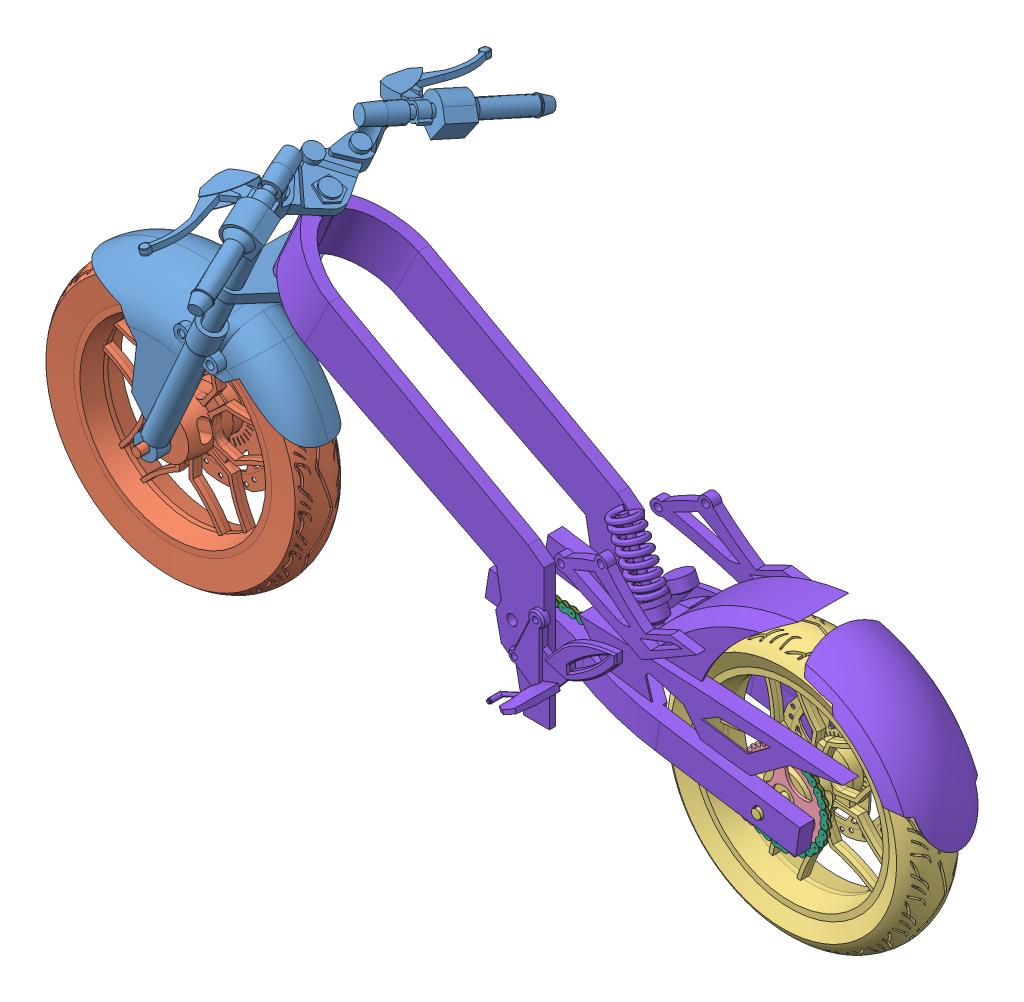
SolidWorks assembly Electric two wheeler, configuration Default. Lengths in mm.
Overall size (2197.87 1236.33 788.52).
90 component instances, 8 part files, 0 mates.
Components (placement in the parent):
- Electric two wheeler.asm-1: Electric two wheeler.asm [Default] at origin size (2197.87 1236.33 788.52)
  - RS 200 HANDLE BARS_0.par-1: RS 200 HANDLE BARS_0.par [Default] at (-2.4024 36.4669 0) x (0 0 -1) z (0.912692 -0.408647 0) size (788.52 788.56 502.86)
  - RS 200 wheel 1_0.par-1: RS 200 wheel 1_0.par [Default] at (-10.5753 18.2131 0) x (0.678244 0.734836 0) z (0 0 -1) size (605.54 605.71 250)
  - RS 200 wheel 2_0.par-1: RS 200 wheel 2_0.par [Default] at (1342.468 10.7356 0) x (-0.818471 0.574548 0) z (0 0 -1) size (598.74 598.38 250)
  - RS200 CHAIN ASSEMBLY_0.asm-1: RS200 CHAIN ASSEMBLY_0.asm [Default] at (1342.468 10.7356 63) x (0.986561 -0.163391 0) z (0 0 1) size (769.44 261.39 9)
    - RS200 45T_0.par-1: RS200 45T_0.par [Default] x (-0.88643 0.462862 0) z (0 0 1) size (193.8 193.68 6)
    - RS200 15T_0.par-1: RS200 15T_0.par [Default] at (-594 0 0) x (-0.272025 0.96229 0) z (0 0 1) size (72.25 71.85 6)
    - RS200 LINK MAIN_0.par-1: RS200 LINK MAIN_0.par [Default] at (-37.6918 -87.6334 0) x (-0.994799 0.101861 0) z (0 0 -1) size (37.05 18 9)
    - RS200 LINK MAIN_0.par-2: RS200 LINK MAIN_0.par [Default] at (0.2544 -91.0166 0) x (-0.994213 -0.10743 0) z (0 0 -1) size (37.05 18 9)
    - RS200 LINK MAIN_0.par-3: RS200 LINK MAIN_0.par [Default] at (37.293 -83.026 0) x (-0.864315 -0.50295 0) z (0 0 -1) size (37.05 18 9)
    - RS200 LINK MAIN_0.par-4: RS200 LINK MAIN_0.par [Default] at (67.8685 -60.6462 0) x (-0.584624 -0.811305 0) z (0 0 -1) size (37.05 18 9)
    - RS200 LINK MAIN_0.par-5: RS200 LINK MAIN_0.par [Default] at (86.6816 -27.7558 0) x (-0.203611 -0.979052 0) z (0 0 -1) size (37.05 18 9)
    - RS200 LINK MAIN_0.par-6: RS200 LINK MAIN_0.par [Default] at (90.472 9.945 0) x (0.212689 -0.97712 0) z (0 0 -1) size (37.05 18 9)
    - RS200 LINK MAIN_0.par-7: RS200 LINK MAIN_0.par [Default] at (78.5827 45.9221 0) x (0.592128 -0.805844 0) z (0 0 -1) size (37.05 18 9)
    - RS200 LINK MAIN_0.par-8: RS200 LINK MAIN_0.par [Default] at (53.0743 73.9406 0) x (0.868946 -0.494907 0) z (0 0 -1) size (37.05 18 9)
    - RS200 LINK MAIN_0.par-9: RS200 LINK MAIN_0.par [Default] at (18.3675 89.1444 0) x (0.995167 -0.098198 0) z (0 0 -1) size (37.05 18 9)
    - RS200 LINK MAIN_0.par-10: RS200 LINK MAIN_0.par [Default] at (-19.5791 89.4881 0) x (0.994799 0.101861 0) z (0 0 -1) size (37.05 18 9)
    - RS200 LINK MAIN_0.par-11: RS200 LINK MAIN_0.par [Default] at (-57.4809 85.6071 0) x (0.994799 0.101861 0) z (0 0 -1) size (37.05 18 9)
    - RS200 LINK MAIN_0.par-12: RS200 LINK MAIN_0.par [Default] at (-95.3827 81.7262 0) x (0.994799 0.101861 0) z (0 0 -1) size (37.05 18 9)
    - RS200 LINK MAIN_0.par-13: RS200 LINK MAIN_0.par [Default] at (-133.2846 77.8453 0) x (0.994799 0.101861 0) z (0 0 -1) size (37.05 18 9)
    - RS200 LINK MAIN_0.par-14: RS200 LINK MAIN_0.par [Default] at (-171.1864 73.9644 0) x (0.994799 0.101861 0) z (0 0 -1) size (37.05 18 9)
    - RS200 LINK MAIN_0.par-15: RS200 LINK MAIN_0.par [Default] at (-209.0882 70.0834 0) x (0.994799 0.101861 0) z (0 0 -1) size (37.05 18 9)
    - RS200 LINK MAIN_0.par-16: RS200 LINK MAIN_0.par [Default] at (-246.99 66.2025 0) x (0.994799 0.101861 0) z (0 0 -1) size (37.05 18 9)
    - RS200 LINK MAIN_0.par-17: RS200 LINK MAIN_0.par [Default] at (-284.8919 62.3216 0) x (0.994799 0.101861 0) z (0 0 -1) size (37.05 18 9)
    - RS200 LINK MAIN_0.par-18: RS200 LINK MAIN_0.par [Default] at (-322.7937 58.4407 0) x (0.994799 0.101861 0) z (0 0 -1) size (37.05 18 9)
    - RS200 LINK MAIN_0.par-19: RS200 LINK MAIN_0.par [Default] at (-360.6955 54.5598 0) x (0.994799 0.101861 0) z (0 0 -1) size (37.05 18 9)
    - RS200 LINK MAIN_0.par-20: RS200 LINK MAIN_0.par [Default] at (-398.5973 50.6788 0) x (0.994799 0.101861 0) z (0 0 -1) size (37.05 18 9)
    - RS200 LINK MAIN_0.par-21: RS200 LINK MAIN_0.par [Default] at (-436.4992 46.7979 0) x (0.994799 0.101861 0) z (0 0 -1) size (37.05 18 9)
    - RS200 LINK MAIN_0.par-22: RS200 LINK MAIN_0.par [Default] at (-474.401 42.917 0) x (0.994799 0.101861 0) z (0 0 -1) size (37.05 18 9)
    - RS200 LINK MAIN_0.par-23: RS200 LINK MAIN_0.par [Default] at (-512.3028 39.0361 0) x (0.994799 0.101861 0) z (0 0 -1) size (37.05 18 9)
    - RS200 LINK MAIN_0.par-24: RS200 LINK MAIN_0.par [Default] at (-550.2047 35.1552 0) x (0.994799 0.101861 0) z (0 0 -1) size (37.05 18 9)
    - RS200 LINK MAIN_0.par-25: RS200 LINK MAIN_0.par [Default] at (-588.1065 31.2742 0) x (0.982131 0.188198 0) z (0 0 -1) size (37.05 18 9)
    - RS200 LINK MAIN_0.par-26: RS200 LINK MAIN_0.par [Default] at (-620.742 14.6902 0) x (0.183791 0.982965 0) z (0 0 -1) size (37.05 18 9)
    - RS200 LINK MAIN_0.par-27: RS200 LINK MAIN_0.par [Default] at (-615.9549 -21.1877 0) x (-0.884353 0.466819 0) z (0 0 -1) size (37.05 18 9)
    - RS200 LINK MAIN_0.par-28: RS200 LINK MAIN_0.par [Default] at (-580.1639 -32.0875 0) x (-0.994799 0.101861 0) z (0 0 -1) size (37.05 18 9)
    - RS200 LINK MAIN_0.par-29: RS200 LINK MAIN_0.par [Default] at (-542.2621 -35.9684 0) x (-0.994799 0.101861 0) z (0 0 -1) size (37.05 18 9)
    - RS200 LINK MAIN_0.par-30: RS200 LINK MAIN_0.par [Default] at (-504.3603 -39.8493 0) x (-0.994799 0.101861 0) z (0 0 -1) size (37.05 18 9)
    - RS200 LINK MAIN_0.par-31: RS200 LINK MAIN_0.par [Default] at (-466.4585 -43.7303 0) x (-0.994799 0.101861 0) z (0 0 -1) size (37.05 18 9)
    - RS200 LINK MAIN_0.par-32: RS200 LINK MAIN_0.par [Default] at (-428.5566 -47.6112 0) x (-0.994799 0.101861 0) z (0 0 -1) size (37.05 18 9)
    - RS200 LINK MAIN_0.par-33: RS200 LINK MAIN_0.par [Default] at (-390.6548 -51.4921 0) x (-0.994799 0.101861 0) z (0 0 -1) size (37.05 18 9)
    - RS200 LINK MAIN_0.par-34: RS200 LINK MAIN_0.par [Default] at (-352.753 -55.373 0) x (-0.994799 0.101861 0) z (0 0 -1) size (37.05 18 9)
    - RS200 LINK MAIN_0.par-35: RS200 LINK MAIN_0.par [Default] at (-314.8511 -59.254 0) x (-0.994799 0.101861 0) z (0 0 -1) size (37.05 18 9)
    - RS200 LINK MAIN_0.par-36: RS200 LINK MAIN_0.par [Default] at (-276.9493 -63.1349 0) x (-0.994799 0.101861 0) z (0 0 -1) size (37.05 18 9)
    - RS200 LINK MAIN_0.par-37: RS200 LINK MAIN_0.par [Default] at (-239.0475 -67.0158 0) x (-0.994799 0.101861 0) z (0 0 -1) size (37.05 18 9)
    - RS200 LINK MAIN_0.par-38: RS200 LINK MAIN_0.par [Default] at (-201.1457 -70.8967 0) x (-0.994799 0.101861 0) z (0 0 -1) size (37.05 18 9)
    - RS200 LINK MAIN_0.par-39: RS200 LINK MAIN_0.par [Default] at (-163.2438 -74.7776 0) x (-0.994799 0.101861 0) z (0 0 -1) size (37.05 18 9)
    - RS200 LINK MAIN_0.par-40: RS200 LINK MAIN_0.par [Default] at (-125.342 -78.6586 0) x (-0.994799 0.101861 0) z (0 0 -1) size (37.05 18 9)
    - RS200 LINK MAIN_0.par-41: RS200 LINK MAIN_0.par [Default] at (-87.4402 -82.5395 0) x (-0.994799 0.101861 0) z (0 0 -1) size (37.05 18 9)
    - RS200 LINK SECONDARY_0.par-1: RS200 LINK SECONDARY_0.par [Default] at (-56.6427 -85.693 0) x (-0.994799 0.101861 0) z (0 0 -1) size (37.05 18 6)
    - RS200 LINK SECONDARY_0.par-2: RS200 LINK SECONDARY_0.par [Default] at (-18.7409 -89.5739 0) x (-0.997128 0.075733 0) z (0 0 -1) size (37.05 18 6)
    - RS200 LINK SECONDARY_0.par-3: RS200 LINK SECONDARY_0.par [Default] at (19.1941 -88.97 0) x (-0.950074 -0.312025 0) z (0 0 -1) size (37.05 18 6)
    - RS200 LINK SECONDARY_0.par-4: RS200 LINK SECONDARY_0.par [Default] at (53.7582 -73.4448 0) x (-0.740693 -0.671843 0) z (0 0 -1) size (37.05 18 6)
    - RS200 LINK SECONDARY_0.par-5: RS200 LINK SECONDARY_0.par [Default] at (79.0055 -45.1908 0) x (-0.402943 -0.915225 0) z (0 0 -1) size (37.05 18 6)
    - RS200 LINK SECONDARY_0.par-6: RS200 LINK SECONDARY_0.par [Default] at (90.5604 -9.1048 0) x (0.004641 -0.999989 0) z (0 0 -1) size (37.05 18 6)
    - RS200 LINK SECONDARY_0.par-7: RS200 LINK SECONDARY_0.par [Default] at (86.4203 28.5591 0) x (0.41142 -0.911446 0) z (0 0 -1) size (37.05 18 6)
    - RS200 LINK SECONDARY_0.par-8: RS200 LINK SECONDARY_0.par [Default] at (67.3027 61.2735 0) x (0.746897 -0.66494 0) z (0 0 -1) size (37.05 18 6)
    - RS200 LINK SECONDARY_0.par-9: RS200 LINK SECONDARY_0.par [Default] at (36.5208 83.3685 0) x (0.952929 -0.303193 0) z (0 0 -1) size (37.05 18 6)
    - RS200 LINK SECONDARY_0.par-10: RS200 LINK SECONDARY_0.par [Default] at (-0.5904 91.015 0) x (0.996782 0.080156 0) z (0 0 -1) size (37.05 18 6)
    - RS200 LINK SECONDARY_0.par-11: RS200 LINK SECONDARY_0.par [Default] at (-38.53 87.5476 0) x (0.994799 0.101861 0) z (0 0 -1) size (37.05 18 6)
    - RS200 LINK SECONDARY_0.par-12: RS200 LINK SECONDARY_0.par [Default] at (-76.4318 83.6667 0) x (0.994799 0.101861 0) z (0 0 -1) size (37.05 18 6)
    - RS200 LINK SECONDARY_0.par-13: RS200 LINK SECONDARY_0.par [Default] at (-114.3336 79.7858 0) x (0.994799 0.101861 0) z (0 0 -1) size (37.05 18 6)
    - RS200 LINK SECONDARY_0.par-14: RS200 LINK SECONDARY_0.par [Default] at (-152.2355 75.9048 0) x (0.994799 0.101861 0) z (0 0 -1) size (37.05 18 6)
    - RS200 LINK SECONDARY_0.par-15: RS200 LINK SECONDARY_0.par [Default] at (-190.1373 72.0239 0) x (0.994799 0.101861 0) z (0 0 -1) size (37.05 18 6)
    - RS200 LINK SECONDARY_0.par-16: RS200 LINK SECONDARY_0.par [Default] at (-228.0391 68.143 0) x (0.994799 0.101861 0) z (0 0 -1) size (37.05 18 6)
    - RS200 LINK SECONDARY_0.par-17: RS200 LINK SECONDARY_0.par [Default] at (-265.941 64.2621 0) x (0.994799 0.101861 0) z (0 0 -1) size (37.05 18 6)
    - RS200 LINK SECONDARY_0.par-18: RS200 LINK SECONDARY_0.par [Default] at (-303.8428 60.3811 0) x (0.994799 0.101861 0) z (0 0 -1) size (37.05 18 6)
    - RS200 LINK SECONDARY_0.par-19: RS200 LINK SECONDARY_0.par [Default] at (-341.7446 56.5002 0) x (0.994799 0.101861 0) z (0 0 -1) size (37.05 18 6)
    - RS200 LINK SECONDARY_0.par-20: RS200 LINK SECONDARY_0.par [Default] at (-379.6464 52.6193 0) x (0.994799 0.101861 0) z (0 0 -1) size (37.05 18 6)
    - RS200 LINK SECONDARY_0.par-21: RS200 LINK SECONDARY_0.par [Default] at (-417.5483 48.7384 0) x (0.994799 0.101861 0) z (0 0 -1) size (37.05 18 6)
    - RS200 LINK SECONDARY_0.par-22: RS200 LINK SECONDARY_0.par [Default] at (-455.4501 44.8575 0) x (0.994799 0.101861 0) z (0 0 -1) size (37.05 18 6)
    - RS200 LINK SECONDARY_0.par-23: RS200 LINK SECONDARY_0.par [Default] at (-493.3519 40.9765 0) x (0.994799 0.101861 0) z (0 0 -1) size (37.05 18 6)
    - RS200 LINK SECONDARY_0.par-24: RS200 LINK SECONDARY_0.par [Default] at (-531.2537 37.0956 0) x (0.994799 0.101861 0) z (0 0 -1) size (37.05 18 6)
    - RS200 LINK SECONDARY_0.par-25: RS200 LINK SECONDARY_0.par [Default] at (-569.1556 33.2147 0) x (0.994799 0.101861 0) z (0 0 -1) size (37.05 18 6)
    - RS200 LINK SECONDARY_0.par-26: RS200 LINK SECONDARY_0.par [Default] at (-606.8161 27.6891 0) x (0.73102 0.682356 0) z (0 0 -1) size (37.05 18 6)
    - RS200 LINK SECONDARY_0.par-27: RS200 LINK SECONDARY_0.par [Default] at (-624.2432 -4.0353 0) x (-0.435085 0.90039 0) z (0 0 -1) size (37.05 18 6)
    - RS200 LINK SECONDARY_0.par-28: RS200 LINK SECONDARY_0.par [Default] at (-599.1079 -30.0806 0) x (-0.994436 0.105347 0) z (0 0 -1) size (37.05 18 6)
    - RS200 LINK SECONDARY_0.par-29: RS200 LINK SECONDARY_0.par [Default] at (-561.213 -34.028 0) x (-0.994799 0.101861 0) z (0 0 -1) size (37.05 18 6)
    - RS200 LINK SECONDARY_0.par-30: RS200 LINK SECONDARY_0.par [Default] at (-523.3112 -37.9089 0) x (-0.994799 0.101861 0) z (0 0 -1) size (37.05 18 6)
    - RS200 LINK SECONDARY_0.par-31: RS200 LINK SECONDARY_0.par [Default] at (-485.4094 -41.7898 0) x (-0.994799 0.101861 0) z (0 0 -1) size (37.05 18 6)
    - RS200 LINK SECONDARY_0.par-32: RS200 LINK SECONDARY_0.par [Default] at (-447.5075 -45.6707 0) x (-0.994799 0.101861 0) z (0 0 -1) size (37.05 18 6)
    - RS200 LINK SECONDARY_0.par-33: RS200 LINK SECONDARY_0.par [Default] at (-409.6057 -49.5516 0) x (-0.994799 0.101861 0) z (0 0 -1) size (37.05 18 6)
    - RS200 LINK SECONDARY_0.par-34: RS200 LINK SECONDARY_0.par [Default] at (-371.7039 -53.4326 0) x (-0.994799 0.101861 0) z (0 0 -1) size (37.05 18 6)
    - RS200 LINK SECONDARY_0.par-35: RS200 LINK SECONDARY_0.par [Default] at (-333.8021 -57.3135 0) x (-0.994799 0.101861 0) z (0 0 -1) size (37.05 18 6)
    - RS200 LINK SECONDARY_0.par-36: RS200 LINK SECONDARY_0.par [Default] at (-295.9002 -61.1944 0) x (-0.994799 0.101861 0) z (0 0 -1) size (37.05 18 6)
    - RS200 LINK SECONDARY_0.par-37: RS200 LINK SECONDARY_0.par [Default] at (-257.9984 -65.0753 0) x (-0.994799 0.101861 0) z (0 0 -1) size (37.05 18 6)
    - RS200 LINK SECONDARY_0.par-38: RS200 LINK SECONDARY_0.par [Default] at (-220.0966 -68.9563 0) x (-0.994799 0.101861 0) z (0 0 -1) size (37.05 18 6)
    - RS200 LINK SECONDARY_0.par-39: RS200 LINK SECONDARY_0.par [Default] at (-182.1948 -72.8372 0) x (-0.994799 0.101861 0) z (0 0 -1) size (37.05 18 6)
    - RS200 LINK SECONDARY_0.par-40: RS200 LINK SECONDARY_0.par [Default] at (-144.2929 -76.7181 0) x (-0.994799 0.101861 0) z (0 0 -1) size (37.05 18 6)
    - RS200 LINK SECONDARY_0.par-41: RS200 LINK SECONDARY_0.par [Default] at (-106.3911 -80.599 0) x (-0.994799 0.101861 0) z (0 0 -1) size (37.05 18 6)
  - RS 200 swing arm_0.par-1: RS 200 swing arm_0.par [Default] at origin size (1488.72 673.69 445.26)
